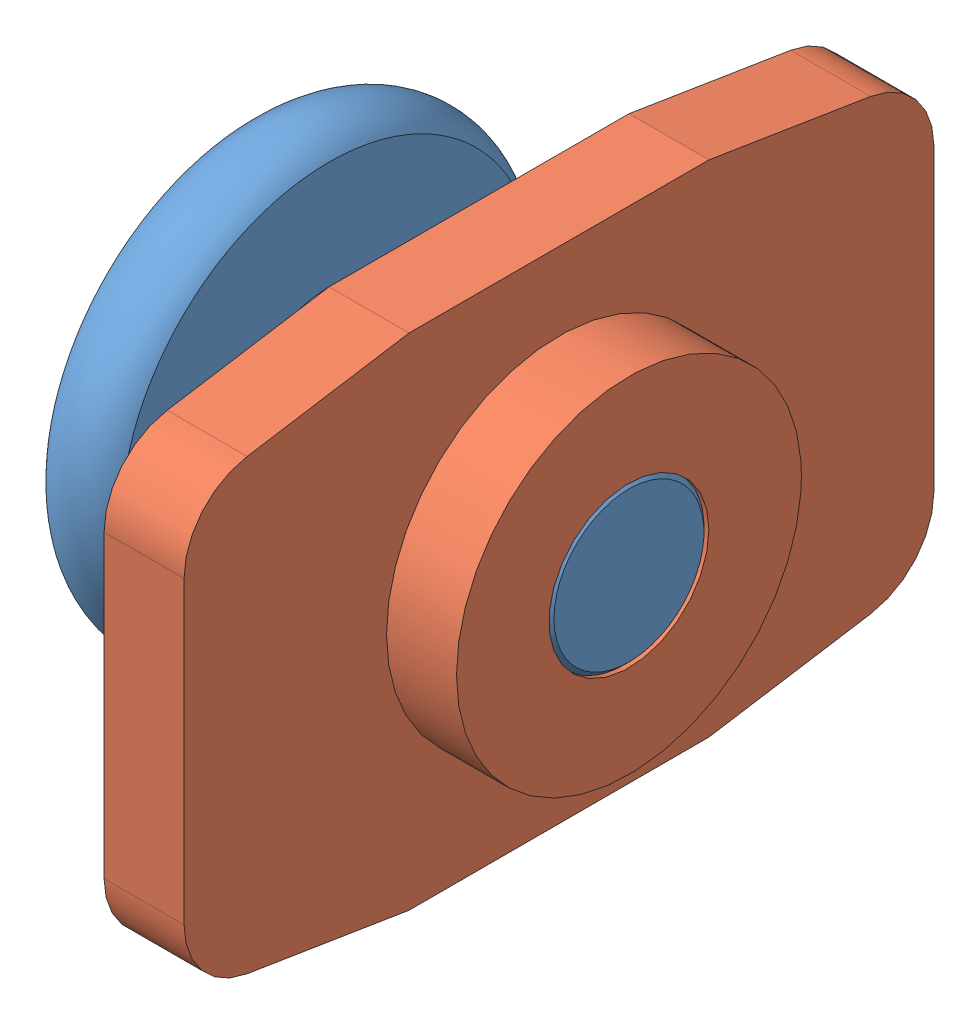
SolidWorks assembly M4_Low_Profile_Screw_with_T_nut, configuration M4-10mm. Lengths in mm.
Overall size (11.62 10 15).
2 component instances, 2 part files, 2 mates.
Components (placement in the parent):
- Low Profile Screw M4-1: Low Profile Screw M4 [M5 x 10] at (4.1063 1.1517 0.1173)
- Tee Nut M4-1: Tee Nut M4 [Default] at (1.1063 1.1517 0.1173) x (0 0 -1) z (1 0 0)
Mates (geometry in assembly coordinates):
- Concentric1: concentric aligned: circle of Low Profile Screw M4-1; circle of Tee Nut M4-1
- Coincident1: coincident aligned: plane of Low Profile Screw M4-1 through (4.1063 1.1517 0.1173) normal (1 0 0); plane of Tee Nut M4-1 through (4.1063 1.1517 0.1173) normal (1 0 0)
